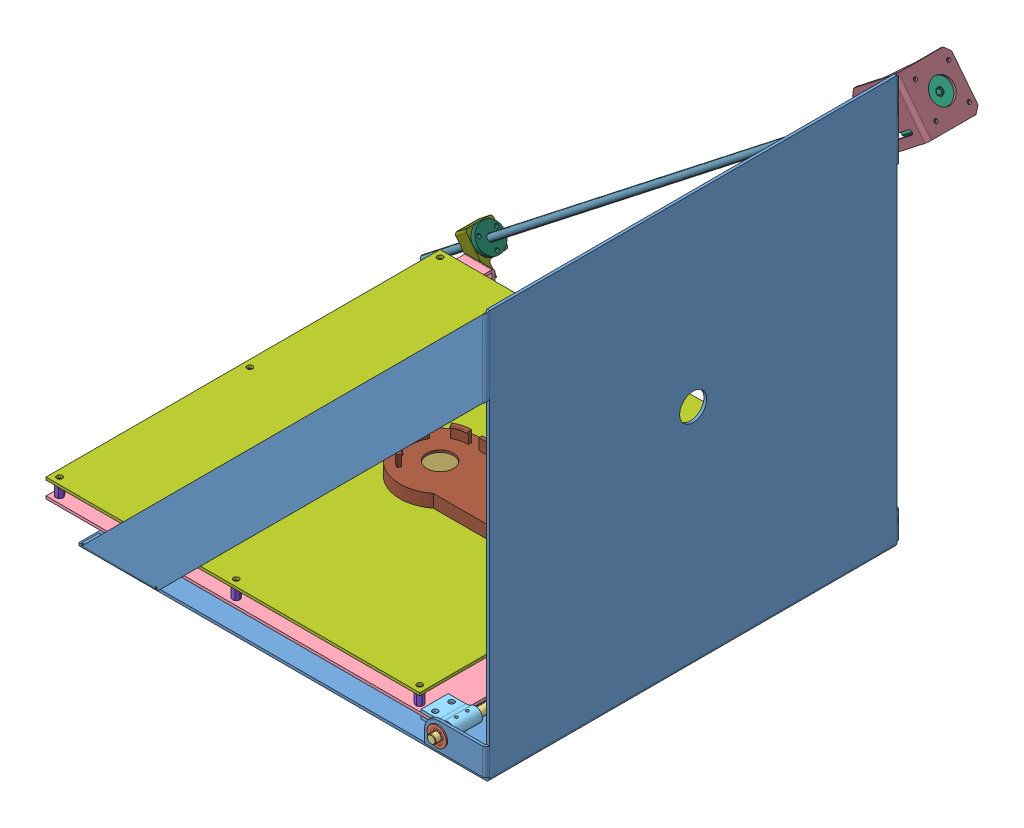
SolidWorks assembly FullAssembly, configuration Default. Lengths in mm.
Overall size (502.33 405.33 443.82).
32 component instances, 16 part files, 15 mates.
Components (placement in the parent):
- MainBody-1: MainBody [Default] at (-120.318 81.6869 482.0329) size (383.55 381.88 389.39)
- 8mmBallBearing-1: 8mmBallBearing [7804K147] at (218.4473 96.3181 483.9095) x (-0.923728 -0.383049 0) z (0 0 -1) size (18 18 5)
- 8mmBallBearing-2: 8mmBallBearing [7804K147] at (218.4473 96.3181 99.1563) size (18 18 5)
- 8mmShaft-1: 8mmShaft [Default] at (218.4473 96.3181 91.5763) x (1 0 0) z (0 -1 0) size (8 400 8)
- WrenchPlateAssem-1: WrenchPlateAssem [Default] at (-260.9378 -98.9937 415.5372) x (0 0 -1) z (1 0.00004 0) size (394.21 74.37 382.46)
  - WrenchPlate-1: WrenchPlate [Default] at (-60.1457 196.6895 471.773) size (394.21 19.05 368.3)
  - ShaftPanelHolder-1: ShaftPanelHolder [Default] at (282.7543 195.2925 479.393) x (0 -1 0) z (0 0 1) size (13.08 25.4 31.94)
  - ShaftPanelHolder-2: ShaftPanelHolder [Default] at (111.3043 195.2925 479.393) x (0 -1 0) z (0 0 1) size (13.08 25.4 31.94)
  - ShaftPanelHolder-3: ShaftPanelHolder [Default] at (-60.1457 195.2925 479.393) x (0 -1 0) z (0 0 1) size (13.08 25.4 31.94)
  - StepperMotorNEMA17-1: StepperMotorNEMA17 [Default] at (161.6983 194.1495 291.0354) x (-1 0 0) z (0 1 0) size (41.78 41.78 53.06)
  - BackPlate-1: BackPlate [Default] at (-60.1457 211.9295 471.773) x (0 -1 0) z (0 0 1) size (2.54 368.3 349.25)
  - HexStandoff#6-1: HexStandoff#6 [91115A127] at (301.8043 203.0395 109.823) x (1 0 0) z (0 1 0) size (6.35 7.33 13.79)
  - HexStandoff#6-2: HexStandoff#6 [91115A127] at (301.8043 203.0395 274.923) x (1 0 0) z (0 1 0) size (6.35 7.33 13.79)
  - HexStandoff#6-3: HexStandoff#6 [91115A127] at (301.8043 203.0395 446.373) x (1 0 0) z (0 -1 0) size (6.35 7.33 13.79)
  - HexStandoff#6-4: HexStandoff#6 [91115A127] at (124.0043 203.0395 446.373) x (1 0 0) z (0 -1 0) size (6.35 7.33 13.79)
  - HexStandoff#6-5: HexStandoff#6 [91115A127] at (-53.7957 203.0395 446.373) x (0.932602 0 0.360906) z (0 -1 0) size (6.35 7.33 13.79)
  - HexStandoff#6-6: HexStandoff#6 [91115A127] at (-53.7957 203.0395 274.923) x (1 0 0) z (0 -1 0) size (6.35 7.33 13.79)
  - HexStandoff#6-7: HexStandoff#6 [91115A127] at (124.0043 203.0395 109.823) x (1 0 0) z (0 -1 0) size (6.35 7.33 13.79)
  - HexStandoff#6-8: HexStandoff#6 [91115A127] at (-53.7957 203.0395 109.823) x (0.996245 0 -0.086583) z (0 1 0) size (6.35 7.33 13.79)
  - StepperGearPitch241-1: StepperGearPitch241 [6832K62] at (161.6983 208.6275 291.0354) x (1 0 0) z (0 1 0) size (27.46 27.46 11.12)
  - 8mmBallBearing-1: 8mmBallBearing [7804K147] at (124.0043 195.5495 287.623) x (-0.837169 0 -0.546944) z (0 1 0) size (18 18 5)
  - 8mmBallBearing-2: 8mmBallBearing [7804K147] at (124.0043 210.5295 287.623) x (1 0 0) z (0 -1 0) size (18 18 5)
  - StepperGearPitch24-2: StepperGearPitch24 [6832K65] at (124.0043 208.6275 287.623) x (-0.837169 0 -0.546944) z (0 1 0) size (52.9 52.9 11.14)
  - WrenchHolderAssem-1: WrenchHolderAssem [Default] at (99.2433 158.6164 216.5098) size (75 47.9 111.45)
    - WrenchHolderV2-1: WrenchHolderV2 [Default] at (24.761 54.4131 71.1131) size (75 22.5 111.45)
    - Electromagnet-1: Electromagnet [Default] at (24.761 54.4131 71.1131) x (0.998284 0 -0.058561) z (0.058561 0 0.998284) size (70 35.4 70)
- NEMA17 - Steel Motor Mount-2: NEMA17 - Steel Motor Mount [Default] at (273.3707 437.6149 97.7563) x (-0.615819 0.787887 0) z (0 0 -1) size (50 54 62.2)
- StepperMotorNEMA17-1: StepperMotorNEMA17 [Default] at (245.1686 415.5719 68.7563) x (0.615819 -0.787887 0) z (-0.787887 -0.615819 0) size (41.78 41.78 53.06)
- LeadScrew-1: LeadScrew [Default] at (229.3568 403.2133 68.7563) x (0.294766 -0.377127 0.878003) z (0.540691 -0.691767 -0.478656) size (6.35 558.8 6.35)
- Threaded Rod End-1: Threaded Rod End [Default] at (-164.0303 121.45 46.1075) x (-0.787887 -0.615819 0) z (0 0 1) size (26.07 38.1 25.4)
  - 6350K166_ULTRA-PRECISION LEAD SCREW-1: 6350K166_ULTRA-PRECISION LEAD SCREW [6350K166] at (-3.8393 20.2576 22.6489) size (26.07 25.4 25.4)
  - LeadScrewAdapter-1: LeadScrewAdapter [Default] at (13.6232 32.9576 35.3489) x (0 1 0) z (0 0 1) size (38.1 12.7 25.4)
Mates (geometry in assembly coordinates):
- Coincident1: coincident anti-aligned: circle of MainBody-1; circle of 8mmBallBearing-1
- Coincident2: coincident anti-aligned: circle of MainBody-1; circle of 8mmBallBearing-2
- Concentric1: concentric anti-aligned: cylinder of 8mmBallBearing-2 through (218.4473 96.3181 101.6563) axis (0 0 1) radius 4; cylinder of 8mmShaft-1 through (218.4473 96.3181 491.5763) axis (0 0 -1) radius 4
- Distance1: distance = 5.08 mm aligned: plane of 8mmBallBearing-2 through (218.4473 104.0681 96.6563) normal (0 0 -1); plane of 8mmShaft-1 through (218.4473 96.3181 91.5763) normal (0 0 -1)
- Concentric2: concentric anti-aligned: cylinder of 8mmShaft-1 through (218.4473 96.3181 491.5763) axis (0 0 -1) radius 4; cylinder of WrenchPlateAssem-1/ShaftPanelHolder-3 through (218.4473 96.3181 450.2829) axis (0 0 1) radius 4
- Distance2: distance = 6.35 mm aligned: plane of WrenchPlateAssem-1/ShaftPanelHolder-1 through (209.4944 82.2207 107.3829) normal (0 0 -1); plane of MainBody-1 through (-120.318 79.1469 101.0329) normal (0 0 -1)
- Concentric5: concentric anti-aligned: circle of MainBody-1; circle of NEMA17 - Steel Motor Mount-2
- Coincident3: coincident anti-aligned: plane of MainBody-1 through (688.5473 96.1181 97.7563) normal (0 0 -1); plane of NEMA17 - Steel Motor Mount-2 through (246.2203 384.6635 97.7563) normal (0 0 1)
- Concentric6: concentric aligned: circle of NEMA17 - Steel Motor Mount-2; circle of StepperMotorNEMA17-1
- Coincident4: coincident anti-aligned: plane of NEMA17 - Steel Motor Mount-2 through (286.5601 416.1934 47.7563) normal (-0.787887 -0.615819 0); plane of StepperMotorNEMA17-1 through (271.1646 435.8906 68.7563) normal (0.787887 0.615819 0)
- Parallel5: parallel: line of NEMA17 - Steel Motor Mount-2 through (285.6871 421.8571 47.7563) axis (-0.615819 0.787887 0); plane of StepperMotorNEMA17-1 through (251.4176 441.6871 48.8808) normal (0 0 -1)
- Concentric7: concentric anti-aligned: circle of StepperMotorNEMA17-1; circle of LeadScrew-1
- Coincident9: coincident aligned: plane of StepperMotorNEMA17-1 through (229.3568 403.2133 68.7563) normal (-0.787887 -0.615819 0); circle of LeadScrew-1
- Concentric12: concentric anti-aligned: cylinder of LeadScrew-1 through (-210.9146 59.0935 68.7563) axis (0.787887 0.615819 0) radius 3.175; circle of Threaded Rod End-1/6350K166_ULTRA-PRECISION LEAD SCREW-1
- Concentric13: concentric aligned: circle of WrenchPlateAssem-1/WrenchPlate-1; circle of Threaded Rod End-1/LeadScrewAdapter-1
